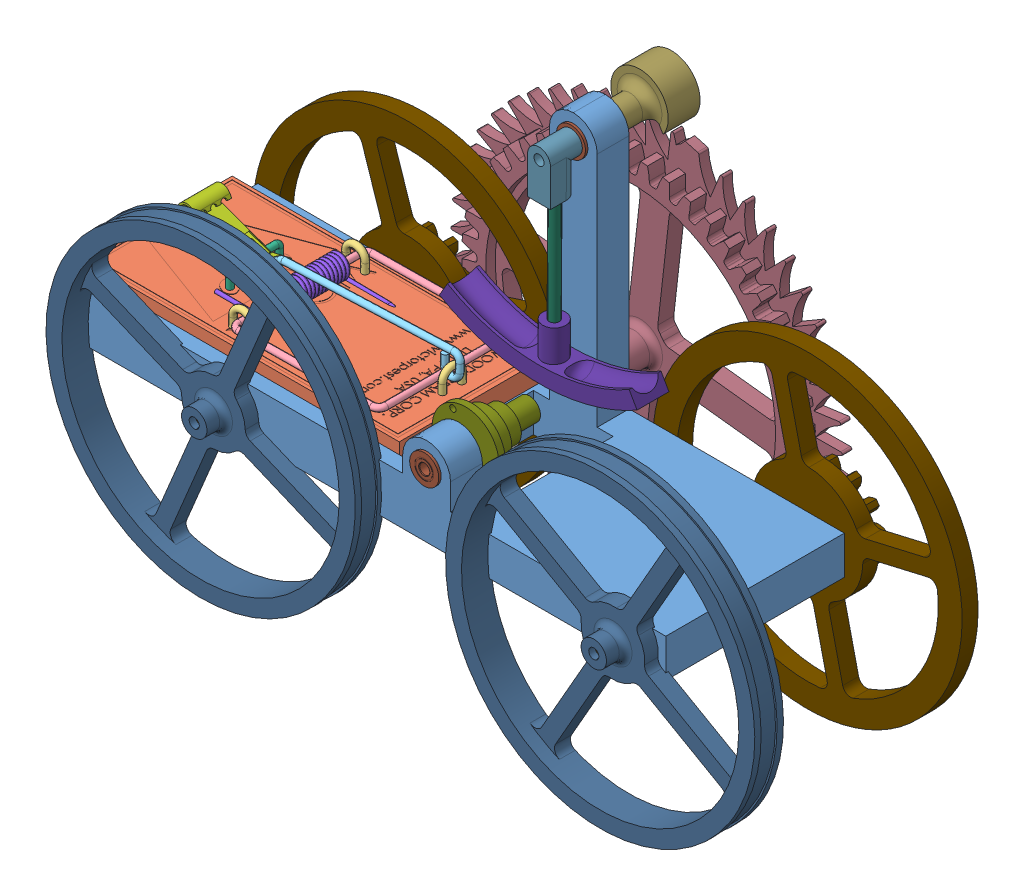
SolidWorks assembly car, configuration Default. Lengths in mm.
Overall size (254.92 158.44 87).
32 component instances, 19 part files, 40 mates.
Components (placement in the parent):
- frame-1: frame [Default] at (-3.5017 38.5263 36.8865) size (183.96 93.7 56)
- mousetrap-1: mousetrap [Défaut] at (-40.4959 50.5263 87.8865) size (98.4 21.67 46)
  - base-1: base [Défaut] at origin size (98.4 6 46)
  - pin-1: pin [Défaut] at (44 6 -5.3) x (-1 0 0) z (0 0 -1) size (8 7 2)
  - pin-2: pin [Défaut] at (44 6 -40.7) x (-1 0 0) z (0 0 -1) size (8 7 2)
  - pin-3: pin [Défaut] at (92 6 -23) x (-0.013039 0 0.999915) z (-0.999915 0 -0.013039) size (8 7 2)
  - trap-1: trap [Défaut] at (66.9989 9.2282 -23) x (0 0 1) z (-0.009923 0.999951 0) size (44 48 2)
  - arm-1: arm [Défaut] at (89.5696 14.2374 -23.2051) x (0.999591 0.024114 -0.015382) z (0.014267 0.045739 0.998852) size (69.37 8.9 2)
  - large_pin-1: large_pin [Défaut] at (30 6 -30.7) x (0 0 1) z (-1 0 0) size (17.4 5.5 2)
  - release-1: release [Défaut] at (14.2602 17.032 -28.5) x (0.942578 -0.333987 0) z (0 0 1) size (26 6.8 11)
  - spring-1: spring [Défaut] at (44 9 -36.0414) x (0 0 1) z (0.011661 0.999932 0) size (25.2 40.12 9.19)
- axle-1: axle [Default] at (8.8434 44.7235 26.1245) x (-0.415407 0.909636 0) z (0 0 1) size (3.17 3.17 75)
- axle-2: axle [Default] at (134.1532 44.7235 26.1245) x (0.212781 -0.9771 0) z (0 0 1) size (3.17 3.17 75)
- big_wheel-1: big_wheel [Default] at (134.1532 44.7235 92.1245) x (0.868348 -0.495955 0) z (0 0 1) size (97 97 11)
- big_wheel-2: big_wheel [Default] at (8.8434 44.7235 92.1245) x (-0.922795 0.385291 0) z (0 0 1) size (97 97 11)
- bearing_1-8in x 5-16in-1: bearing_1-8in x 5-16in [4262T27] at (134.1532 44.7235 37.9105) x (0.256729 -0.966483 0) z (0 0 1) size (9.12 9.12 3.57)
- bearing_1-8in x 5-16in-2: bearing_1-8in x 5-16in [4262T27] at (134.1532 44.7235 93.6781) x (0.834756 0.55062 0) z (0 0 -1) size (9.12 9.12 3.57)
- bearing_1-8in x 5-16in-3: bearing_1-8in x 5-16in [4262T27] at (8.8434 44.7235 37.9105) x (0.676416 0.73652 0) z (0 0 1) size (9.12 9.12 3.57)
- bearing_1-8in x 5-16in-4: bearing_1-8in x 5-16in [4262T27] at (8.8434 44.7235 94.0696) x (0.016339 -0.999867 0) z (0 0 -1) size (9.12 9.12 3.57)
- bearing_1-8in x 5-16in-6: bearing_1-8in x 5-16in [4262T27] at (71.4983 58.7235 37.9105) x (-0.603714 -0.797201 0) z (0 0 1) size (9.12 9.12 3.57)
- escapement_tic_tac-1: escapement_tic_tac [Default] at (75.857 116.4682 26.1245) x (-0.869659 -0.493653 0) z (0 0 -1) size (18 17 20)
- 48T_12P-2: 48T_12P [6867K67] at (71.4983 58.7235 28.9122) x (0.993643 -0.112576 0) z (0 0 1) size (122.73 122.73 17)
- pendulum_top_holder-1: pendulum_top_holder [Default] at (71.4983 124.7235 47.6485) x (0.999989 -0.004719 0) z (0 0 1) size (7.17 15.28 10)
- bearing_1-8in x 5-16in-7: bearing_1-8in x 5-16in [4262T27] at (71.4983 124.7235 45.8626) x (-0.306917 -0.951736 0) z (0 0 -1) size (9.12 9.12 3.57)
- bearing_1-8in x 5-16in-8: bearing_1-8in x 5-16in [4262T27] at (71.4983 124.7235 37.9105) x (0.840845 -0.541275 0) z (0 0 1) size (9.12 9.12 3.57)
- bearing_1-8in x 5-16in-9: bearing_1-8in x 5-16in [4262T27] at (71.4983 58.7235 91.8626) x (0.068903 -0.997623 0) z (0 0 -1) size (9.12 9.12 3.57)
- pendulum_arm-1: pendulum_arm [Default] at (71.2355 69.0366 52.6485) x (-0.273848 0.001292 0.961772) z (0.004719 0.999989 0) size (3.17 3.17 52.1)
- escapement_gear-1: escapement_gear [6867K67] at (118.9606 94.7482 21.1245) x (-0.998626 -0.052398 0) z (0 0 1) size (122.73 122.73 5) (hidden)
- pulley-1: pulley [Default] at (71.4983 58.7235 60.6765) x (0.896865 0.442304 0) z (0 0 1) size (21 21 20)
- pendulum_bottom-1: pendulum_bottom [Default] at (71.2827 79.0365 52.6485) x (0.999989 -0.004719 0) z (0 0 1) size (62 15 10)
- 12T_gear_wheel-1: 12T_gear_wheel [6325K22] at (8.8434 44.7235 26.1245) x (0.949269 0.314466 0) z (0 0 -1) size (97.02 97.02 10)
- 12T_gear_wheel-2: 12T_gear_wheel [6325K22] at (134.1532 44.7235 26.1245) x (0.974154 0.225886 0) z (0 0 -1) size (97.02 97.02 10)
Mates (geometry in assembly coordinates):
- Concentric30: concentric aligned: cylinder of axle-2 through (134.1532 44.7235 101.1245) axis (0 0 -1) radius 1.5875; cylinder of big_wheel-1 through (134.1532 44.7235 101.1245) axis (0 0 -1) radius 1.5875
- Coincident13: coincident aligned: plane of axle-2 through (134.1532 44.7235 101.1245) normal (0 0 1); plane of big_wheel-1 through (134.1532 44.7235 101.1245) normal (0 0 1)
- Coincident15: coincident aligned: plane of axle-1 through (8.8434 44.7235 101.1245) normal (0 0 1); plane of big_wheel-2 through (8.8434 44.7235 101.1245) normal (0 0 1)
- Concentric31: concentric aligned: cylinder of axle-1 through (8.8434 44.7235 101.1245) axis (0 0 -1) radius 1.5875; cylinder of big_wheel-2 through (8.8434 44.7235 101.1245) axis (0 0 -1) radius 1.5875
- Coincident14: coincident aligned: plane of frame-1 through (-3.5017 50.5263 36.8865) normal (0 0 -1); circle of bearing_1-8in x 5-16in-1
- Coincident18: coincident aligned: plane of frame-1 through (-3.5017 50.5263 36.8865) normal (0 0 -1); circle of bearing_1-8in x 5-16in-3
- Concentric41: concentric aligned: cylinder of axle-1 through (8.8434 44.7235 101.1245) axis (0 0 -1) radius 1.5875; cylinder of bearing_1-8in x 5-16in-4 through (8.8434 44.7235 92.2837) axis (0 0 -1) radius 1.5875
- Concentric42: concentric anti-aligned: cylinder of axle-2 through (134.1532 44.7235 101.1245) axis (0 0 -1) radius 1.5875; cylinder of bearing_1-8in x 5-16in-1 through (134.1532 44.7235 39.6964) axis (0 0 1) radius 1.5875
- Coincident34: coincident anti-aligned: plane of frame-1 through (-3.5017 50.5263 36.8865) normal (0 1 0); plane of mousetrap-1/base-1 through (-40.4959 50.5263 87.8865) normal (0 -1 0)
- Concentric69: concentric anti-aligned: cylinder of bearing_1-8in x 5-16in-7 through (71.4983 124.7235 44.0767) axis (0 0 -1) radius 1.5875; cylinder of bearing_1-8in x 5-16in-8 through (71.4983 124.7235 39.6964) axis (0 0 1) radius 3.9688
- Parallel4: parallel aligned: plane of frame-1 through (-3.5017 50.5263 92.8865) normal (0 0 1); plane of mousetrap-1/base-1 through (-40.4959 56.5263 87.8865) normal (0 0 1)
- Concentric70: concentric anti-aligned: cylinder of pendulum_top_holder-1 through (71.4431 113.0317 52.6485) axis (0.004719 0.999989 0) radius 1.5875; cylinder of pendulum_arm-1 through (71.4814 121.136 52.6485) axis (-0.004719 -0.999989 0) radius 1.5875
- Tangent7: tangent anti-aligned: cylinder of pendulum_top_holder-1 through (71.4983 124.7235 57.6485) axis (0 0 -1) radius 3.5875; plane of pendulum_arm-1 through (71.4814 121.136 52.6485) normal (0.004719 0.999989 0)
- Concentric72: concentric aligned: cylinder of pendulum_top_holder-1 through (71.4983 124.7235 57.6485) axis (0 0 -1) radius 1.5875; cylinder of bearing_1-8in x 5-16in-7 through (71.4983 124.7235 44.0767) axis (0 0 -1) radius 1.5875
- Coincident52: coincident aligned: circle of frame-1; circle of bearing_1-8in x 5-16in-3
- Coincident53: coincident aligned: circle of frame-1; circle of bearing_1-8in x 5-16in-1
- Concentric76: concentric anti-aligned: cylinder of axle-1 through (8.8434 44.7235 101.1245) axis (0 0 -1) radius 1.5875; cylinder of bearing_1-8in x 5-16in-3 through (8.8434 44.7235 39.6964) axis (0 0 1) radius 1.5875
- Concentric77: concentric aligned: cylinder of bearing_1-8in x 5-16in-6 through (71.4983 58.7235 39.6964) axis (0 0 1) radius 1.5875; cylinder of 48T_12P-2 through (71.4983 58.7235 23.9122) axis (0 0 1) radius 1.6
- Concentric79: concentric aligned: cylinder of escapement_tic_tac-1 through (71.4983 124.7235 16.1245) axis (0 0 1) radius 1.6; cylinder of bearing_1-8in x 5-16in-8 through (71.4983 124.7235 39.6964) axis (0 0 1) radius 1.5875
- Concentric80: concentric aligned: cylinder of axle-2 through (134.1532 44.7235 101.1245) axis (0 0 -1) radius 1.5875; cylinder of bearing_1-8in x 5-16in-2 through (134.1532 44.7235 91.8921) axis (0 0 -1) radius 1.5875
- Concentric81: concentric anti-aligned: cylinder of 48T_12P-2 through (71.4983 58.7235 23.9122) axis (0 0 1) radius 1.6; cylinder of bearing_1-8in x 5-16in-9 through (71.4983 58.7235 90.0767) axis (0 0 -1) radius 1.5875
- Concentric82: concentric aligned: cylinder of frame-1 through (71.4983 58.7235 92.8865) axis (0 0 -1) radius 3.9688; cylinder of escapement_gear-1 through (71.4983 58.7235 26.1245) axis (0 0 -1) radius 1.5875
- Concentric83: concentric aligned: cylinder of escapement_gear-1 through (71.4983 58.7235 26.1245) axis (0 0 -1) radius 1.5875; cylinder of pulley-1 through (71.4983 58.7235 80.6765) axis (0 0 -1) radius 1.5875
- Concentric85: concentric anti-aligned: cylinder of pendulum_arm-1 through (71.4814 121.136 52.6485) axis (-0.004719 -0.999989 0) radius 1.5875; cylinder of pendulum_bottom-1 through (71.2355 69.0366 52.6485) axis (0.004719 0.999989 0) radius 1.5875
- Tangent10: tangent aligned: plane of pendulum_arm-1 through (71.2355 69.0366 52.6485) normal (-0.004719 -0.999989 0); cylinder of pendulum_bottom-1 through (71.5045 126.036 47.6485) axis (0 0 1) radius 57
- Parallel5: parallel aligned: plane of pendulum_top_holder-1 through (71.4983 124.7235 57.6485) normal (0 0 1); plane of pendulum_bottom-1 through (71.5045 126.036 57.6485) normal (0 0 1)
- Concentric86: concentric aligned: cylinder of axle-1 through (8.8434 44.7235 101.1245) axis (0 0 -1) radius 1.5875; cylinder of 12T_gear_wheel-1 through (8.8434 44.7235 31.1245) axis (0 0 -1) radius 1.5875
- Concentric87: concentric aligned: cylinder of axle-2 through (134.1532 44.7235 101.1245) axis (0 0 -1) radius 1.5875; cylinder of 12T_gear_wheel-2 through (134.1532 44.7235 31.1245) axis (0 0 -1) radius 1.5875
- Coincident69: coincident anti-aligned: plane of bearing_1-8in x 5-16in-1 through (137.8163 45.6965 36.1245) normal (0 0 -1); plane of 12T_gear_wheel-2 through (134.1532 44.7235 36.1245) normal (0 0 1)
- Coincident70: coincident anti-aligned: plane of bearing_1-8in x 5-16in-3 through (6.0518 47.2872 36.1245) normal (0 0 -1); plane of 12T_gear_wheel-1 through (8.8434 44.7235 36.1245) normal (0 0 1)
- Coincident72: coincident anti-aligned: circle of frame-1; circle of bearing_1-8in x 5-16in-7
- Coincident76: coincident aligned: circle of frame-1; circle of bearing_1-8in x 5-16in-6
- Coincident77: coincident anti-aligned: plane of pendulum_top_holder-1 through (71.4983 124.7235 47.6485) normal (0 0 -1); plane of bearing_1-8in x 5-16in-7 through (67.8911 125.8867 47.6485) normal (0 0 1)
- Coincident78: coincident aligned: plane of axle-1 through (8.8434 44.7235 26.1245) normal (0 0 -1); plane of 12T_gear_wheel-1 through (8.8434 44.7235 26.1245) normal (0 0 -1)
- Coincident79: coincident aligned: plane of axle-2 through (134.1532 44.7235 26.1245) normal (0 0 -1); plane of 12T_gear_wheel-2 through (134.1532 44.7235 26.1245) normal (0 0 -1)
- Coincident80: coincident anti-aligned: circle of frame-1; circle of bearing_1-8in x 5-16in-9
- Coincident81: coincident aligned: circle of frame-1; circle of bearing_1-8in x 5-16in-8
- Coincident82: coincident aligned: plane of escapement_tic_tac-1 through (75.857 116.4682 26.1245) normal (0 0 1); plane of escapement_gear-1 through (118.9606 94.7482 26.1245) normal (0 0 1)
- Distance1: distance = 5 mm aligned: plane of frame-1 through (-3.5017 50.5263 36.8865) normal (0 0 -1); plane of mousetrap-1/base-1 through (-40.4959 56.5263 41.8865) normal (0 0 -1)
- Coincident85: coincident anti-aligned: plane of escapement_gear-1 through (118.9606 94.7482 26.1245) normal (0 0 1); plane of 12T_gear_wheel-2 through (134.1532 44.7235 26.1245) normal (0 0 -1)
